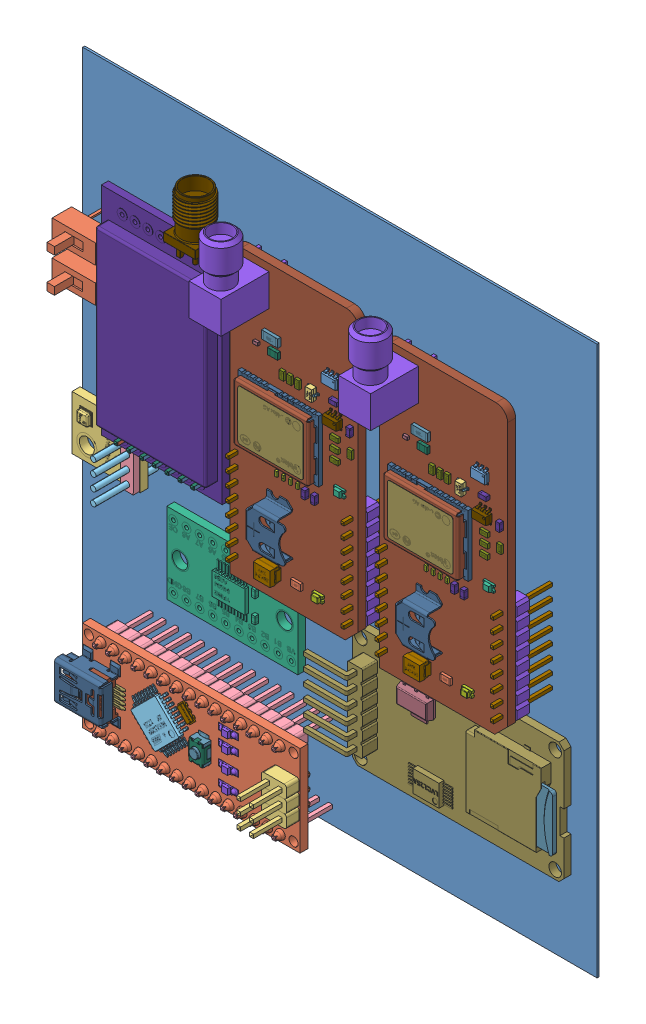
SolidWorks assembly PCB1 STEP, configuration Default. Lengths in mm.
Overall size (102.11 108.97 21.15).
253 component instances, 56 part files, 0 mates.
Components (placement in the parent):
- Board-1: Board [Default] at origin size (102.11 108.97 0.41)
  - Open CASCADE STEP translator 6.8 2.1.1-1: Open CASCADE STEP translator 6.8 2.1.1 [Default] at (0 0 -0.4115) size (102.11 108.97 0.41)
- arduino_nano-1: arduino_nano [Default] at (0 0 6.3234) size (45 18 18.6)
  - arduino_nano-1: arduino_nano [Default] at (189.4641 68.814 2.5274) x (-1 0 0) z (0 1 0) size (45 18.6 18)
    - nano-board-1: nano-board [Default] at origin size (43.2 4.61 18)
    - 2pin_header__02-1: 2pin_header__02 [Default] at (-1.143 1.6 -7.62) size (5 11.75 2.54)
    - 2pin_header__02-2: 2pin_header__02 [Default] at (-1.143 1.6 -5.08) size (5 11.75 2.54)
    - 2pin_header__02-3: 2pin_header__02 [Default] at (-1.143 1.6 -10.16) size (5 11.75 2.54)
    - 15pin_header__-1: 15pin_header__ [Default] x (0 0 1) z (1 0 0) size (2.54 11.75 38.1)
    - 15pin_header__-2: 15pin_header__ [Default] at (0 0 -15.24) x (0 0 1) z (1 0 0) size (2.54 11.75 38.1)
    - atmega328-1: atmega328 [Default] at (23.85 1.75 -7.62) x (-0.707107 0 0.707107) z (-0.707107 0 -0.707107) size (10 1.1 10)
    - ftdi_FT232rl-1: ftdi_FT232rl [Default] at (29.05 0 -7.67) x (0 0 -1) z (-1 0 0) size (9.25 1.9 10.2)
    - smt_resistor222-1: smt_resistor222 [Default] at (21.86 0 -5.8) x (0 0 -1) z (-1 0 0) size (1.7 0.6 3.8)
    - smt_resistor222-2: smt_resistor222 [Default] at (21.86 0 -9) x (0 0 -1) z (-1 0 0) size (1.7 0.6 3.8)
    - smt_resistor222-3: smt_resistor222 [Default] at (36.75 0 -7.6) x (0 0 -1) z (-1 0 0) size (1.7 0.6 3.8)
    - smt_resistor222-4: smt_resistor222 [Default] at (36.75 0 -12) x (0 0 -1) z (-1 0 0) size (1.7 0.6 3.8)
    - smt_resistor222-5: smt_resistor222 [Default] at (8.2 0 -2.6) x (0 0 -1) z (-1 0 0) size (1.7 0.6 3.8)
    - led-1: led [Default] at (10.4 1.6 -2.8) size (4 0.9 1.55)
    - led-2: led [Default] at (10.4 1.6 -5.55) size (4 0.9 1.55)
    - led-3: led [Default] at (10.4 1.6 -12.5) size (4 0.9 1.55)
    - led-4: led [Default] at (10.4 1.6 -9.05) size (4 0.9 1.55)
    - 16mhz_crystal_-_measured-1: 16mhz_crystal_-_measured [Default] at (18.5113 1.6 -3.5541) x (0.707107 0 0.707107) z (-0.707107 0 0.707107) size (3.4 0.8 2.01)
    - MINIUSB_-_MEASURED-1: MINIUSB_-_MEASURED [Default] at (38.98 1.65 -7.62) x (0 0 1) z (-1 0 0) size (10.9 4.96 10.42)
      - MINIUSBSHELL-1: MINIUSBSHELL [Default] at origin size (10.9 3.98 9.46)
      - MINIUSBCORE-1: MINIUSBCORE [Default] at (0 0 6.7) x (-1 0 0) z (0 0 -1) size (7.7 4.5 8.2)
      - MINI_USB_CONTACT-1: MINI_USB_CONTACT [Default] at (-1.6 0 5.7) x (-1 0 0) z (0 0 -1) size (0.53 2.55 9.41)
      - MINI_USB_CONTACT-2: MINI_USB_CONTACT [Default] at (-0.8 0 5.7) x (-1 0 0) z (0 0 -1) size (0.53 2.55 9.41)
      - MINI_USB_CONTACT-3: MINI_USB_CONTACT [Default] at (0 0 5.7) x (-1 0 0) z (0 0 -1) size (0.53 2.55 9.41)
      - MINI_USB_CONTACT-4: MINI_USB_CONTACT [Default] at (0.8 0 5.7) x (-1 0 0) z (0 0 -1) size (0.53 2.55 9.41)
      - MINI_USB_CONTACT-5: MINI_USB_CONTACT [Default] at (1.6 0 5.7) x (-1 0 0) z (0 0 -1) size (0.53 2.55 9.41)
    - cap106C-1: cap106C [Default] at (37.2 0 -3.3) x (0 0 1) z (1 0 0) size (1.7 1.81 4)
    - cap106C-2: cap106C [Default] at (7.9 0 -5.6) x (0 0 -1) z (-1 0 0) size (1.7 1.81 4)
    - reset_button-1: reset_button [Default] at (15.25 1.6 -8.05) x (0 0 -1) z (1 0 0) size (5.21 2.15 3)
      - reset_core-1: reset_core [Default] at origin size (5.21 2.15 2.8)
      - reset_shell-1: reset_shell [Default] at (0 1.65 0) x (0 0 1) z (-1 0 0) size (3 1.65 4)
    - nano_-_reg-1: nano_-_reg [Default] at (6.1 0 -10.16) x (0 0 -1) z (-1 0 0) size (6.5 1.69 8.3)
    - NANO_DIODE-1: NANO_DIODE [Default] at (11.43 0 -4.2) x (0 0 1) z (1 0 0) size (4.92 1.38 1.7)
    - 189_RESISTOR_PACK-1: 189_RESISTOR_PACK [Default] at (15.75 0 -10.85) x (0 0 1) z (1 0 0) size (3.2 0.51 3)
    - 102_RESISTOR_PACK-1: 102_RESISTOR_PACK [Default] at (15.75 0 -5.2) x (0 0 1) z (1 0 0) size (3.2 0.51 3)
- M0-1: M0 [Default] at (0 0 4.4267) size (8.61 3.85 12.07)
  - SS12D00G4_1P2T_Straight-1: SS12D00G4_1P2T_Straight [Default] at (146.8249 131.405 2.54) x (1 0 0) z (0 0 1) size (8.61 3.85 12.07)
- BMP-1: BMP [Default] at (0 0 2.9006) size (13.55 10.7 12.7)
  - GY-BME280-1: GY-BME280 [Default] at (155.5751 97.6629 0) x (0 1 0) z (0 0 1) size (10.7 13.55 3.64)
  - 1185083472-1: 1185083472 [Default] at (154.178 97.536 0) size (2.54 10.16 2.8)
    - Extruded-1: Extruded [Default] at origin size (2.54 10.16 2.8)
  - 1185083552-1: 1185083552 [Default] at (154.1779 93.7261 -3.2) x (0 1 0) z (0 0 1) size (1.06 1.06 12.7)
    - Cylinder-1: Cylinder [Default] at origin size (1.06 1.06 12.7)
  - 1185083552-2: 1185083552 [Default] at (154.1779 96.2661 -3.2) x (0 1 0) z (0 0 1) size (1.06 1.06 12.7)
    - Cylinder-1: Cylinder [Default] at origin size (1.06 1.06 12.7)
  - 1185083552-3: 1185083552 [Default] at (154.1779 98.8061 -3.2) x (0 1 0) z (0 0 1) size (1.06 1.06 12.7)
    - Cylinder-1: Cylinder [Default] at origin size (1.06 1.06 12.7)
  - 1185083552-4: 1185083552 [Default] at (154.1779 101.3461 -3.2) x (0 1 0) z (0 0 1) size (1.06 1.06 12.7)
    - Cylinder-1: Cylinder [Default] at origin size (1.06 1.06 12.7)
- LVL_CONV-1: LVL_CONV [Default] at origin size (26 16 2.26)
  - TXS0108E-1: TXS0108E [Default] at (183.8961 73.6876 0) x (-1 0 0) z (0 1 0) size (26 2.26 16)
- GPS-1: GPS [Default] at (0 0 9.8364) size (25.78 64.21 19.66)
  - GNSS_7_Click_v100_noAntenna-1: GNSS_7_Click_v100_noAntenna [Default] at (180.3023 96.7993 0.254) x (1 0 0) z (0 0 1) size (25.78 64.21 19.66)
    - GNSS_7_Click_v100.step-1: GNSS_7_Click_v100.step [Default] at origin size (25.78 64.21 19.66)
      - JP4.step-1: JP4.step [Default] at origin size (0.5 1 0.35)
        - User_Library-R_0402.step-1: User_Library-R_0402.step [Default] at (12.3191 18.1685 0) x (0 -1 0) z (0 0 1) size (1 0.5 0.35)
      - JP3.step-1: JP3.step [Default] at origin size (0.5 1 0.35)
        - User_Library-R_0402.step-1: User_Library-R_0402.step [Default] at (10.9221 18.161 0) x (0 -1 0) z (0 0 1) size (1 0.5 0.35)
      - JP2.step-1: JP2.step [Default] at origin size (0.5 1 0.35)
        - User_Library-R_0402.step-1: User_Library-R_0402.step [Default] at (9.5251 18.1685 0) x (0 -1 0) z (0 0 1) size (1 0.5 0.35)
      - JP1.step-1: JP1.step [Default] at origin size (0.5 1 0.35)
        - User_Library-R_0402.step-1: User_Library-R_0402.step [Default] at (8.1281 18.1685 0) x (0 -1 0) z (0 0 1) size (1 0.5 0.35)
      - MBD1.step-1: MBD1.step [Default] at origin size (25.78 20.32 12.19)
        - Header_1x8.step-1: Header_1x8.step [Default] at (-74.8548 -67.056 0) size (2.92 20.32 12.19)
          - PCB.step-1: PCB.step [Default] at origin size (2.92 20.32 12.19)
            - Free-Models.step-1: Free-Models.step [Default] at origin size (2.92 20.32 12.19)
              - 1240637040.step-1: 1240637040.step [Default] at (97.7778 84.836 -1.6002) x (0 -1 0) z (1 0 0) size (12.7 12.19 2.92)
                - User_Library-PinHeaderX5-1_PinHeaderX5_Body_1.step-1: User_Library-PinHeaderX5-1_PinHeaderX5_Body_1.step [Default] at origin size (12.7 2.54 2.92)
                - User_Library-PinHeaderX5-1_PinHeaderX5_Pins_1.step-1: User_Library-PinHeaderX5-1_PinHeaderX5_Pins_1.step [Default] at origin size (10.8 12.19 0.64)
              - 1240637040.step-2: 1240637040.step [Default] at (97.7778 77.216 -1.6002) x (0 -1 0) z (1 0 0) size (12.7 12.19 2.92)
                - User_Library-PinHeaderX5-1_PinHeaderX5_Body_1.step-1: User_Library-PinHeaderX5-1_PinHeaderX5_Body_1.step [Default] at origin size (12.7 2.54 2.92)
                - User_Library-PinHeaderX5-1_PinHeaderX5_Pins_1.step-1: User_Library-PinHeaderX5-1_PinHeaderX5_Pins_1.step [Default] at origin size (10.8 12.19 0.64)
        - Header_1x8.step-2: Header_1x8.step [Default] at (-97.7148 -67.056 0) size (2.92 20.32 12.19)
          - PCB.step-1: PCB.step [Default] at origin size (2.92 20.32 12.19)
            - Free-Models.step-1: Free-Models.step [Default] at origin size (2.92 20.32 12.19)
              - 1240637040.step-1: 1240637040.step [Default] at (97.7778 84.836 -1.6002) x (0 -1 0) z (1 0 0) size (12.7 12.19 2.92)
                - User_Library-PinHeaderX5-1_PinHeaderX5_Body_1.step-1: User_Library-PinHeaderX5-1_PinHeaderX5_Body_1.step [Default] at origin size (12.7 2.54 2.92)
                - User_Library-PinHeaderX5-1_PinHeaderX5_Pins_1.step-1: User_Library-PinHeaderX5-1_PinHeaderX5_Pins_1.step [Default] at origin size (10.8 12.19 0.64)
              - 1240637040.step-2: 1240637040.step [Default] at (97.7778 77.216 -1.6002) x (0 -1 0) z (1 0 0) size (12.7 12.19 2.92)
                - User_Library-PinHeaderX5-1_PinHeaderX5_Body_1.step-1: User_Library-PinHeaderX5-1_PinHeaderX5_Body_1.step [Default] at origin size (12.7 2.54 2.92)
                - User_Library-PinHeaderX5-1_PinHeaderX5_Pins_1.step-1: User_Library-PinHeaderX5-1_PinHeaderX5_Pins_1.step [Default] at origin size (10.8 12.19 0.64)
      - M1.step-1: M1.step [Default] at origin size (16 12.2 2.33)
        - NEO.step-1: NEO.step [Default] at (27.1803 74.1975 0.44) x (0 1 0) z (0 0 1) size (12.2 16 2.33)
          - NEO_PCB.step-1: NEO_PCB.step [Default] at (-47.5276 18.1124 -0.4125) size (12.2 16 0.9)
          - Shield_NEO.step-1: Shield_NEO.step [Default] at (-52.9276 25.2124 1.8175) x (0 -1 0) z (-1 0 0) size (15 1.4 11.6)
          - u-blox_NEO_label.step-1: u-blox_NEO_label.step [Default] at (-47.5276 18.1124 1.8175) x (0 1 0) z (1 0 0) size (13 0.07 10)
      - L1.step-1: L1.step [Default] at origin size (1 0.6 0.5)
        - User_Library-Chip_InductorINDC1005X60N.step-1: User_Library-Chip_InductorINDC1005X60N.step [Default] at (4.191 38.435 0.2433) x (1 0 0) z (0 0 1) size (1 0.6 0.5)
      - R9.step-1: R9.step [Default] at origin size (3.2 1.6 0.6)
        - User_Library-R_1206.step-1: User_Library-R_1206.step [Default] at (7.197 41.0209 0) x (-1 0 0) z (0 0 1) size (3.2 1.6 0.6)
      - C6.step-1: C6.step [Default] at origin size (2 1.25 0.6)
        - User_Library-SMD_CAPACITOR0805.step-1: User_Library-SMD_CAPACITOR0805.step [Default] at (7.7471 38.7351 0.3) x (1 0 0) z (0 -1 0) size (2 0.6 1.25)
      - R8.step-1: R8.step [Default] at origin size (1.6 0.9 0.5)
        - User_Library-R_0603.step-1: User_Library-R_0603.step [Default] at (19.8119 26.289 0) x (-1 0 0) z (0 0 1) size (1.6 0.9 0.5)
      - C3.step-1: C3.step [Default] at origin size (0.8 1.6 0.8)
        - User_Library-SMD_CAPACITOR0603.step-1: User_Library-SMD_CAPACITOR0603.step [Default] at (15.8749 17.7801 0.39) x (0 1 0) z (0 0 1) size (1.6 0.8 0.8)
      - C2.step-1: C2.step [Default] at origin size (0.8 1.6 0.8)
        - User_Library-SMD_CAPACITOR0603.step-1: User_Library-SMD_CAPACITOR0603.step [Default] at (13.9699 17.7801 0.39) x (0 1 0) z (0 0 1) size (1.6 0.8 0.8)
      - U2.step-1: U2.step [Default] at origin size (2.9 2.8 1.45)
        - User_Library-SOT23-5-2.step-1: User_Library-SOT23-5-2.step [Default] at (19.812 33.2739 0) x (-1 0 0) z (0 0 1) size (2.9 2.8 1.45)
      - U1.step-1: U1.step [Default] at origin size (2.9 2.82 1)
        - TSOT-23-6(S6).step-1: TSOT-23-6(S6).step [Default] at (19.1769 39.878 0) x (0 1 0) z (1 0 0) size (2.82 1 2.9)
      - R7.step-1: R7.step [Default] at origin size (0.9 1.6 0.5)
        - User_Library-R_0603.step-1: User_Library-R_0603.step [Default] at (12.446 35.8141 0) x (0 1 0) z (0 0 1) size (1.6 0.9 0.5)
      - R6.step-1: R6.step [Default] at origin size (0.9 1.6 0.5)
        - User_Library-R_0603.step-1: User_Library-R_0603.step [Default] at (10.922 35.8141 0) x (0 1 0) z (0 0 1) size (1.6 0.9 0.5)
      - R5.step-1: R5.step [Default] at origin size (0.9 1.6 0.5)
        - User_Library-R_0603.step-1: User_Library-R_0603.step [Default] at (9.398 35.8139 0) x (0 -1 0) z (0 0 1) size (1.6 0.9 0.5)
      - R4.step-1: R4.step [Default] at origin size (0.9 1.6 0.5)
        - User_Library-R_0603.step-1: User_Library-R_0603.step [Default] at (22.86 28.9559 0) x (0 -1 0) z (0 0 1) size (1.6 0.9 0.5)
      - R3.step-1: R3.step [Default] at origin size (1.6 0.9 0.5)
        - User_Library-R_0603.step-1: User_Library-R_0603.step [Default] at (19.8119 28.194 0) x (-1 0 0) z (0 0 1) size (1.6 0.9 0.5)
      - R2.step-1: R2.step [Default] at origin size (1.6 0.9 0.5)
        - User_Library-R_0603.step-1: User_Library-R_0603.step [Default] at (19.8119 30.099 0) x (-1 0 0) z (0 0 1) size (1.6 0.9 0.5)
      - R1.step-1: R1.step [Default] at origin size (2 1.25 0.5)
        - User_Library-R_0805.step-1: User_Library-R_0805.step [Default] at (12.1919 1.1429 0) x (-1 0 0) z (0 0 1) size (2 1.25 0.5)
      - Q1.step-1: Q1.step [Default] at origin size (2.25 2.2 1.1)
        - SOT323_(SC70-3)-1.step-1: SOT323_(SC70-3)-1.step [Default] at (15.3671 35.8141 0) x (0 -1 0) z (-1 0 0) size (2.2 1.1 2.25)
          - User_Library-SOT323_(SC70-3)-1_K_X_F6rper_1.step-1: User_Library-SOT323_(SC70-3)-1_K_X_F6rper_1.step [Default] x (0 0 -1) z (0 1 0) size (1.35 2.2 1)
          - User_Library-SOT323_(SC70-3)-1_Beschriftung_1.step-1: User_Library-SOT323_(SC70-3)-1_Beschriftung_1.step [Default] x (0 0 -1) z (0 1 0) size (0.8 1.45 0.06)
          - User_Library-SOT323_(SC70-3)-1_Pins_1.step-1: User_Library-SOT323_(SC70-3)-1_Pins_1.step [Default] at (0.65 0 0) x (0 0 1) z (0 1 0) size (0.6 0.4 0.9)
          - User_Library-SOT323_(SC70-3)-1_Pins_1.step-2: User_Library-SOT323_(SC70-3)-1_Pins_1.step [Default] at (-0.65 0 0) x (0 0 1) z (0 1 0) size (0.6 0.4 0.9)
          - User_Library-SOT323_(SC70-3)-1_Pins_1.step-3: User_Library-SOT323_(SC70-3)-1_Pins_1.step [Default] x (0 0 -1) z (0 1 0) size (0.6 0.4 0.9)
      - LD2.step-1: LD2.step [Default] at origin size (2.1 1.35 0.91)
        - CHIPLED-0805-RED.step-1: CHIPLED-0805-RED.step [Default] at (20.7009 21.3361 0) x (0 1 0) z (0 0 1) size (1.35 2.1 0.91)
      - LD1.step-1: LD1.step [Default] at origin size (2.02 1.25 1.1)
        - led_0805_green.step-1: led_0805_green.step [Default] at (16.5099 1.143 0) x (-1 0 0) z (0 0 1) size (2.02 1.25 1.1)
      - CN2.step-1: CN2.step [Default] at origin size (6.35 14.81 13.49)
        - User_Library-sma_ra_pcb_mount_molex.step-1: User_Library-sma_ra_pcb_mount_molex.step [Default] at (3.302 48.7682 0) x (0 1 0) z (0 0 1) size (14.81 6.35 13.49)
      - C5.step-1: C5.step [Default] at origin size (0.8 1.6 0.8)
        - User_Library-SMD_CAPACITOR0603.step-1: User_Library-SMD_CAPACITOR0603.step [Default] at (22.8791 32.8929 0.39) x (0 -1 0) z (0 0 1) size (1.6 0.8 0.8)
      - C4.step-1: C4.step [Default] at origin size (1.6 0.8 0.8)
        - User_Library-SMD_CAPACITOR0603.step-1: User_Library-SMD_CAPACITOR0603.step [Default] at (19.8121 36.4491 0.39) size (1.6 0.8 0.8)
      - C1.step-1: C1.step [Default] at origin size (3.7 2.93 2.03)
        - User_Library-AVX_BCASE.step-1: User_Library-AVX_BCASE.step [Default] at (7.0351 1.1431 0) x (1 0 0) z (0 0 1) size (3.7 2.93 2.03)
      - BAT1.step-1: BAT1.step [Default] at origin size (8 10.71 3.05)
        - keystone-PN2998TR.step-1: keystone-PN2998TR.step [Default] at (5.2705 9.272 2.9) x (0 -1 0) z (-1 0 0) size (10.71 3.05 8)
      - Board.step-1: Board.step [Default] at origin size (25.4 57.15 1.59)
- GAL-1: GAL [Default] at (0 0 11.1875) size (25.78 64.21 19.66)
  - GNSS_7_Click_v100_noAntenna-1: GNSS_7_Click_v100_noAntenna [Default] at (211.1003 96.5199 0) x (1 0 0) z (0 0 1) size (25.78 64.21 19.66)
    - GNSS_7_Click_v100.step-1: GNSS_7_Click_v100.step [Default] at origin size (25.78 64.21 19.66)
      - JP4.step-1: JP4.step [Default] at origin size (0.5 1 0.35)
        - User_Library-R_0402.step-1: User_Library-R_0402.step [Default] at (12.3191 18.1685 0) x (0 -1 0) z (0 0 1) size (1 0.5 0.35)
      - JP3.step-1: JP3.step [Default] at origin size (0.5 1 0.35)
        - User_Library-R_0402.step-1: User_Library-R_0402.step [Default] at (10.9221 18.161 0) x (0 -1 0) z (0 0 1) size (1 0.5 0.35)
      - JP2.step-1: JP2.step [Default] at origin size (0.5 1 0.35)
        - User_Library-R_0402.step-1: User_Library-R_0402.step [Default] at (9.5251 18.1685 0) x (0 -1 0) z (0 0 1) size (1 0.5 0.35)
      - JP1.step-1: JP1.step [Default] at origin size (0.5 1 0.35)
        - User_Library-R_0402.step-1: User_Library-R_0402.step [Default] at (8.1281 18.1685 0) x (0 -1 0) z (0 0 1) size (1 0.5 0.35)
      - MBD1.step-1: MBD1.step [Default] at origin size (25.78 20.32 12.19)
        - Header_1x8.step-1: Header_1x8.step [Default] at (-74.8548 -67.056 0) size (2.92 20.32 12.19)
          - PCB.step-1: PCB.step [Default] at origin size (2.92 20.32 12.19)
            - Free-Models.step-1: Free-Models.step [Default] at origin size (2.92 20.32 12.19)
              - 1240637040.step-1: 1240637040.step [Default] at (97.7778 84.836 -1.6002) x (0 -1 0) z (1 0 0) size (12.7 12.19 2.92)
                - User_Library-PinHeaderX5-1_PinHeaderX5_Body_1.step-1: User_Library-PinHeaderX5-1_PinHeaderX5_Body_1.step [Default] at origin size (12.7 2.54 2.92)
                - User_Library-PinHeaderX5-1_PinHeaderX5_Pins_1.step-1: User_Library-PinHeaderX5-1_PinHeaderX5_Pins_1.step [Default] at origin size (10.8 12.19 0.64)
              - 1240637040.step-2: 1240637040.step [Default] at (97.7778 77.216 -1.6002) x (0 -1 0) z (1 0 0) size (12.7 12.19 2.92)
                - User_Library-PinHeaderX5-1_PinHeaderX5_Body_1.step-1: User_Library-PinHeaderX5-1_PinHeaderX5_Body_1.step [Default] at origin size (12.7 2.54 2.92)
                - User_Library-PinHeaderX5-1_PinHeaderX5_Pins_1.step-1: User_Library-PinHeaderX5-1_PinHeaderX5_Pins_1.step [Default] at origin size (10.8 12.19 0.64)
        - Header_1x8.step-2: Header_1x8.step [Default] at (-97.7148 -67.056 0) size (2.92 20.32 12.19)
          - PCB.step-1: PCB.step [Default] at origin size (2.92 20.32 12.19)
            - Free-Models.step-1: Free-Models.step [Default] at origin size (2.92 20.32 12.19)
              - 1240637040.step-1: 1240637040.step [Default] at (97.7778 84.836 -1.6002) x (0 -1 0) z (1 0 0) size (12.7 12.19 2.92)
                - User_Library-PinHeaderX5-1_PinHeaderX5_Body_1.step-1: User_Library-PinHeaderX5-1_PinHeaderX5_Body_1.step [Default] at origin size (12.7 2.54 2.92)
                - User_Library-PinHeaderX5-1_PinHeaderX5_Pins_1.step-1: User_Library-PinHeaderX5-1_PinHeaderX5_Pins_1.step [Default] at origin size (10.8 12.19 0.64)
              - 1240637040.step-2: 1240637040.step [Default] at (97.7778 77.216 -1.6002) x (0 -1 0) z (1 0 0) size (12.7 12.19 2.92)
                - User_Library-PinHeaderX5-1_PinHeaderX5_Body_1.step-1: User_Library-PinHeaderX5-1_PinHeaderX5_Body_1.step [Default] at origin size (12.7 2.54 2.92)
                - User_Library-PinHeaderX5-1_PinHeaderX5_Pins_1.step-1: User_Library-PinHeaderX5-1_PinHeaderX5_Pins_1.step [Default] at origin size (10.8 12.19 0.64)
      - M1.step-1: M1.step [Default] at origin size (16 12.2 2.33)
        - NEO.step-1: NEO.step [Default] at (27.1803 74.1975 0.44) x (0 1 0) z (0 0 1) size (12.2 16 2.33)
          - NEO_PCB.step-1: NEO_PCB.step [Default] at (-47.5276 18.1124 -0.4125) size (12.2 16 0.9)
          - Shield_NEO.step-1: Shield_NEO.step [Default] at (-52.9276 25.2124 1.8175) x (0 -1 0) z (-1 0 0) size (15 1.4 11.6)
          - u-blox_NEO_label.step-1: u-blox_NEO_label.step [Default] at (-47.5276 18.1124 1.8175) x (0 1 0) z (1 0 0) size (13 0.07 10)
      - L1.step-1: L1.step [Default] at origin size (1 0.6 0.5)
        - User_Library-Chip_InductorINDC1005X60N.step-1: User_Library-Chip_InductorINDC1005X60N.step [Default] at (4.191 38.435 0.2433) x (1 0 0) z (0 0 1) size (1 0.6 0.5)
      - R9.step-1: R9.step [Default] at origin size (3.2 1.6 0.6)
        - User_Library-R_1206.step-1: User_Library-R_1206.step [Default] at (7.197 41.0209 0) x (-1 0 0) z (0 0 1) size (3.2 1.6 0.6)
      - C6.step-1: C6.step [Default] at origin size (2 1.25 0.6)
        - User_Library-SMD_CAPACITOR0805.step-1: User_Library-SMD_CAPACITOR0805.step [Default] at (7.7471 38.7351 0.3) x (1 0 0) z (0 -1 0) size (2 0.6 1.25)
      - R8.step-1: R8.step [Default] at origin size (1.6 0.9 0.5)
        - User_Library-R_0603.step-1: User_Library-R_0603.step [Default] at (19.8119 26.289 0) x (-1 0 0) z (0 0 1) size (1.6 0.9 0.5)
      - C3.step-1: C3.step [Default] at origin size (0.8 1.6 0.8)
        - User_Library-SMD_CAPACITOR0603.step-1: User_Library-SMD_CAPACITOR0603.step [Default] at (15.8749 17.7801 0.39) x (0 1 0) z (0 0 1) size (1.6 0.8 0.8)
      - C2.step-1: C2.step [Default] at origin size (0.8 1.6 0.8)
        - User_Library-SMD_CAPACITOR0603.step-1: User_Library-SMD_CAPACITOR0603.step [Default] at (13.9699 17.7801 0.39) x (0 1 0) z (0 0 1) size (1.6 0.8 0.8)
      - U2.step-1: U2.step [Default] at origin size (2.9 2.8 1.45)
        - User_Library-SOT23-5-2.step-1: User_Library-SOT23-5-2.step [Default] at (19.812 33.2739 0) x (-1 0 0) z (0 0 1) size (2.9 2.8 1.45)
      - U1.step-1: U1.step [Default] at origin size (2.9 2.82 1)
        - TSOT-23-6(S6).step-1: TSOT-23-6(S6).step [Default] at (19.1769 39.878 0) x (0 1 0) z (1 0 0) size (2.82 1 2.9)
      - R7.step-1: R7.step [Default] at origin size (0.9 1.6 0.5)
        - User_Library-R_0603.step-1: User_Library-R_0603.step [Default] at (12.446 35.8141 0) x (0 1 0) z (0 0 1) size (1.6 0.9 0.5)
      - R6.step-1: R6.step [Default] at origin size (0.9 1.6 0.5)
        - User_Library-R_0603.step-1: User_Library-R_0603.step [Default] at (10.922 35.8141 0) x (0 1 0) z (0 0 1) size (1.6 0.9 0.5)
      - R5.step-1: R5.step [Default] at origin size (0.9 1.6 0.5)
        - User_Library-R_0603.step-1: User_Library-R_0603.step [Default] at (9.398 35.8139 0) x (0 -1 0) z (0 0 1) size (1.6 0.9 0.5)
      - R4.step-1: R4.step [Default] at origin size (0.9 1.6 0.5)
        - User_Library-R_0603.step-1: User_Library-R_0603.step [Default] at (22.86 28.9559 0) x (0 -1 0) z (0 0 1) size (1.6 0.9 0.5)
      - R3.step-1: R3.step [Default] at origin size (1.6 0.9 0.5)
        - User_Library-R_0603.step-1: User_Library-R_0603.step [Default] at (19.8119 28.194 0) x (-1 0 0) z (0 0 1) size (1.6 0.9 0.5)
      - R2.step-1: R2.step [Default] at origin size (1.6 0.9 0.5)
        - User_Library-R_0603.step-1: User_Library-R_0603.step [Default] at (19.8119 30.099 0) x (-1 0 0) z (0 0 1) size (1.6 0.9 0.5)
      - R1.step-1: R1.step [Default] at origin size (2 1.25 0.5)
        - User_Library-R_0805.step-1: User_Library-R_0805.step [Default] at (12.1919 1.1429 0) x (-1 0 0) z (0 0 1) size (2 1.25 0.5)
      - Q1.step-1: Q1.step [Default] at origin size (2.25 2.2 1.1)
        - SOT323_(SC70-3)-1.step-1: SOT323_(SC70-3)-1.step [Default] at (15.3671 35.8141 0) x (0 -1 0) z (-1 0 0) size (2.2 1.1 2.25)
          - User_Library-SOT323_(SC70-3)-1_K_X_F6rper_1.step-1: User_Library-SOT323_(SC70-3)-1_K_X_F6rper_1.step [Default] x (0 0 -1) z (0 1 0) size (1.35 2.2 1)
          - User_Library-SOT323_(SC70-3)-1_Beschriftung_1.step-1: User_Library-SOT323_(SC70-3)-1_Beschriftung_1.step [Default] x (0 0 -1) z (0 1 0) size (0.8 1.45 0.06)
          - User_Library-SOT323_(SC70-3)-1_Pins_1.step-1: User_Library-SOT323_(SC70-3)-1_Pins_1.step [Default] at (0.65 0 0) x (0 0 1) z (0 1 0) size (0.6 0.4 0.9)
          - User_Library-SOT323_(SC70-3)-1_Pins_1.step-2: User_Library-SOT323_(SC70-3)-1_Pins_1.step [Default] at (-0.65 0 0) x (0 0 1) z (0 1 0) size (0.6 0.4 0.9)
          - User_Library-SOT323_(SC70-3)-1_Pins_1.step-3: User_Library-SOT323_(SC70-3)-1_Pins_1.step [Default] x (0 0 -1) z (0 1 0) size (0.6 0.4 0.9)
      - LD2.step-1: LD2.step [Default] at origin size (2.1 1.35 0.91)
        - CHIPLED-0805-RED.step-1: CHIPLED-0805-RED.step [Default] at (20.7009 21.3361 0) x (0 1 0) z (0 0 1) size (1.35 2.1 0.91)
      - LD1.step-1: LD1.step [Default] at origin size (2.02 1.25 1.1)
        - led_0805_green.step-1: led_0805_green.step [Default] at (16.5099 1.143 0) x (-1 0 0) z (0 0 1) size (2.02 1.25 1.1)
      - CN2.step-1: CN2.step [Default] at origin size (6.35 14.81 13.49)
        - User_Library-sma_ra_pcb_mount_molex.step-1: User_Library-sma_ra_pcb_mount_molex.step [Default] at (3.302 48.7682 0) x (0 1 0) z (0 0 1) size (14.81 6.35 13.49)
      - C5.step-1: C5.step [Default] at origin size (0.8 1.6 0.8)
        - User_Library-SMD_CAPACITOR0603.step-1: User_Library-SMD_CAPACITOR0603.step [Default] at (22.8791 32.8929 0.39) x (0 -1 0) z (0 0 1) size (1.6 0.8 0.8)
      - C4.step-1: C4.step [Default] at origin size (1.6 0.8 0.8)
        - User_Library-SMD_CAPACITOR0603.step-1: User_Library-SMD_CAPACITOR0603.step [Default] at (19.8121 36.4491 0.39) size (1.6 0.8 0.8)
      - C1.step-1: C1.step [Default] at origin size (3.7 2.93 2.03)
        - User_Library-AVX_BCASE.step-1: User_Library-AVX_BCASE.step [Default] at (7.0351 1.1431 0) x (1 0 0) z (0 0 1) size (3.7 2.93 2.03)
      - BAT1.step-1: BAT1.step [Default] at origin size (8 10.71 3.05)
        - keystone-PN2998TR.step-1: keystone-PN2998TR.step [Default] at (5.2705 9.272 2.9) x (0 -1 0) z (-1 0 0) size (10.71 3.05 8)
      - Board.step-1: Board.step [Default] at origin size (25.4 57.15 1.59)
- M1-1: M1 [Default] at (0 0 4.463) size (8.61 3.85 12.07)
  - SS12D00G4_1P2T_Straight-1: SS12D00G4_1P2T_Straight [Default] at (146.8249 124.547 2.54) x (1 0 0) z (0 0 1) size (8.61 3.85 12.07)
- SD-1: SD [Default] at (0 0 6.1612) size (46.9 24 6.7)
  - MicroSD_Reader_Assembly-1: MicroSD_Reader_Assembly [Default] at (210.8201 82.6769 0.127) x (-1 0 0) z (0 0 1) size (46.9 24 6.7)
    - sdreader-1: sdreader [Default] at (-11.2744 2.632 -3.2) size (46.9 24 6.7)
      - Open CASCADE STEP translator 6.8 2.9.1.1.1-1: Open CASCADE STEP translator 6.8 2.9.1.1.1 [Default] at origin size (46.9 24 6.7)
    - AMS1117-1: AMS1117 [Default] at (-0.4339 -2.128 -1.13) x (1 0 0) z (0 -1 0) size (6.51 1.86 7)
    - card_sd-1: card_sd [Default] at (-21.187 5.4466 -0.36) x (0 -1 0) z (0 0 1) size (11 15 0.82)
- LoRA_-_ES32-1: LoRA_-_ES32 [Default] at (0 0 3.4049) size (24 52.5 13.62)
  - STEP-7pin-61300711121-rev1-1: STEP-7pin-61300711121-rev1 [Default] at (165.6081 105.664 1.2975) x (1 0 0) z (0 -1 0) size (17.78 11.54 2.54)
    - 6130xx11121_PIN-1: 6130xx11121_PIN [Default] at (-7.62 1.5 0) x (1 0 0) z (0 -1 0) size (0.64 0.64 11.54)
    - 6130xx11121_PIN-2: 6130xx11121_PIN [Default] at (-5.08 1.5 0) x (1 0 0) z (0 -1 0) size (0.64 0.64 11.54)
    - 6130xx11121_PIN-3: 6130xx11121_PIN [Default] at (-2.54 1.5 0) x (1 0 0) z (0 -1 0) size (0.64 0.64 11.54)
    - 6130xx11121_PIN-4: 6130xx11121_PIN [Default] at (0 1.5 0) x (1 0 0) z (0 -1 0) size (0.64 0.64 11.54)
    - 6130xx11121_PIN-5: 6130xx11121_PIN [Default] at (2.54 1.5 0) x (1 0 0) z (0 -1 0) size (0.64 0.64 11.54)
    - 6130xx11121_PIN-6: 6130xx11121_PIN [Default] at (5.08 1.5 0) x (1 0 0) z (0 -1 0) size (0.64 0.64 11.54)
    - 6130xx11121_PIN-7: 6130xx11121_PIN [Default] at (7.62 1.5 0) x (1 0 0) z (0 -1 0) size (0.64 0.64 11.54)
    - 61300711121-1: 61300711121 [Default] at origin size (17.78 2.54 2.54)
  - E32-TTL-1: E32-TTL [Default] at (165.6386 192.5439 25.4) x (0 1 0) z (1 0 0) size (52.5 13.62 24)
    - E32-TTL-1W_Predeterminado-1: E32-TTL-1W_Predeterminado [Default] at (-66.873 -19.9517 0) size (43 3.79 24)
    - SMA_CONNECTOR_-_EMPCB.SMAFSTJ.B.HT-1: SMA_CONNECTOR_-_EMPCB.SMAFSTJ.B.HT [Default] at (-43.773 -15.0017 10.2201) x (0 0 1) z (1 0 0) size (6.58 6.47 13.3)
    - 05__HEADER-3WAY-1ROW-2.54MM-VERTICAL-PCB_Predeterminado-1: 05__HEADER-3WAY-1ROW-2.54MM-VERTICAL-PCB_Predeterminado [Default] at (-87.6961 -24.2405 2.52) x (0 -1 0) z (0 0 1) size (11.55 2.54 7.62)
    - 05__HEADER-3WAY-1ROW-2.54MM-VERTICAL-PCB_Predeterminado-2: 05__HEADER-3WAY-1ROW-2.54MM-VERTICAL-PCB_Predeterminado [Default] at (-87.6961 -24.2405 -5.1) x (0 -1 0) z (0 0 1) size (11.55 2.54 7.62)
    - HEADER-1WAY-1ROW-2.54MM-VERTICAL-PCB_Predeterminado-1: HEADER-1WAY-1ROW-2.54MM-VERTICAL-PCB_Predeterminado [Default] at (-86.893 -19.9517 -7.64) x (0 -1 0) z (-1 0 0) size (11.54 2.54 2.54)
